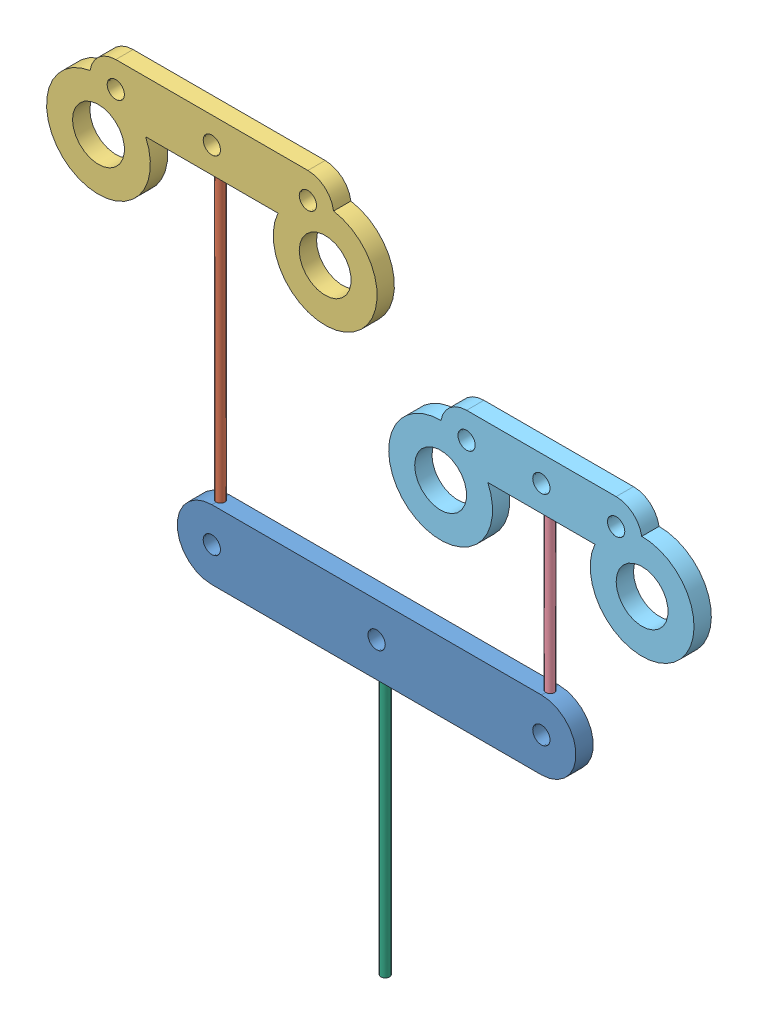
SolidWorks assembly whiffleetree, configuration Default. Lengths in mm.
Overall size (74.83 77 2).
6 component instances, 6 part files, 12 mates.
Components (placement in the parent):
- mainBar-1: mainBar [Default] at (20.3524 18.4625 38.0201) size (46.08 8 2)
- dynema1-1: dynema1 [Default] at (1.3104 55.9625 39.0201) x (0.250397 0 -0.968143) z (0 -1 0) size (1 1 34)
- barIndexMiddle-1: barIndexMiddle [Default] at (1.3104 58.4625 38.0201) size (38.2 14.5 2)
- dynema2-1: dynema2 [Default] at (39.3944 21.9625 39.0201) x (0.365635 0 0.930758) z (0 1 0) size (1 1 19.17)
- barRingPinky-1: barRingPinky [Default] at (39.3944 43.6325 38.0201) size (35.28 14.5 2)
- dynema3-1: dynema3 [Default] at (20.3524 14.9625 39.0201) x (0.922872 0 -0.385106) z (0 -1 0) size (1 1 30.5)
Mates (geometry in assembly coordinates):
- Concentric1: concentric aligned: cylinder of mainBar-1 through (1.3104 21.9625 39.0201) axis (0 1 0) radius 0.5; cylinder of dynema1-1 through (1.3104 21.9625 39.0201) axis (0 1 0) radius 0.5
- Coincident1: coincident anti-aligned: circle of mainBar-1; circle of dynema1-1
- Concentric2: concentric anti-aligned: cylinder of dynema1-1 through (1.3104 21.9625 39.0201) axis (0 1 0) radius 0.5; cylinder of barIndexMiddle-1 through (1.3104 55.9625 39.0201) axis (0 -1 0) radius 0.5
- Coincident2: coincident aligned: plane of mainBar-1 through (1.3104 18.4625 40.0201) normal (0 0 1); plane of barIndexMiddle-1 through (12.4106 58.4625 40.0201) normal (0 0 1)
- Coincident3: coincident aligned: circle of dynema1-1; plane of barIndexMiddle-1 through (1.3104 55.9625 39.0201) normal (0 -1 0)
- Concentric3: concentric anti-aligned: cylinder of mainBar-1 through (39.3944 21.9625 39.0201) axis (0 1 0) radius 0.5; cylinder of dynema2-1 through (39.3944 41.1325 39.0201) axis (0 -1 0) radius 0.5
- Coincident4: coincident aligned: circle of mainBar-1; circle of dynema2-1
- Concentric4: concentric aligned: cylinder of dynema2-1 through (39.3944 41.1325 39.0201) axis (0 -1 0) radius 0.5; cylinder of barRingPinky-1 through (39.3944 41.1325 39.0201) axis (0 -1 0) radius 0.5
- Coincident5: coincident aligned: plane of mainBar-1 through (1.3104 18.4625 40.0201) normal (0 0 1); plane of barRingPinky-1 through (27.7522 38.1325 40.0201) normal (0 0 1)
- Coincident6: coincident anti-aligned: circle of dynema2-1; circle of barRingPinky-1
- Concentric5: concentric anti-aligned: cylinder of mainBar-1 through (20.3524 14.9625 39.0201) axis (0 -1 0) radius 0.5; cylinder of dynema3-1 through (20.3524 -15.5375 39.0201) axis (0 1 0) radius 0.5
- Coincident7: coincident aligned: circle of mainBar-1; circle of dynema3-1
